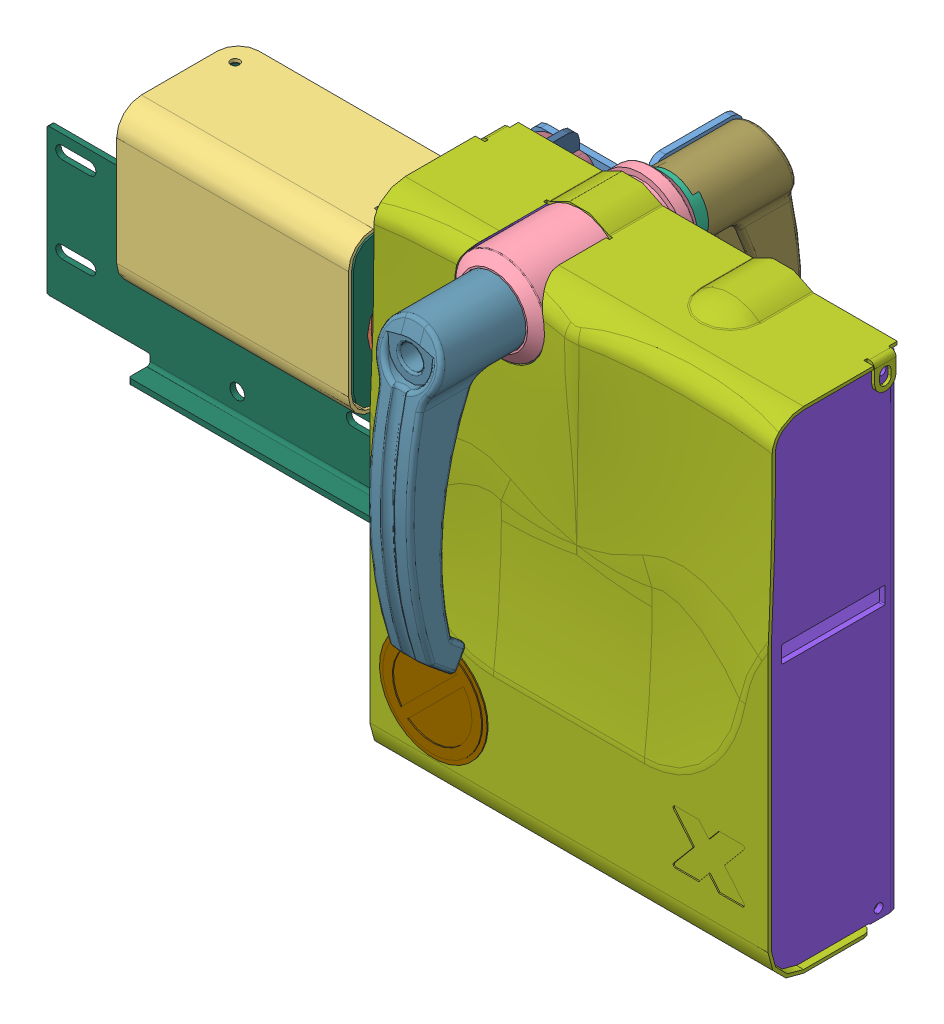
SolidWorks assembly L66-21-R, configuration Default. Lengths in mm.
Overall size (392.28 233 201.49).
16 component instances, 16 part files, 0 mates.
Components (placement in the parent):
- 00010380-1-1: 00010380-1 [Default] at (-32.9953 39.7 -87) x (0 0 -1) z (-1 0 0) size (45.2 80 53.67)
- 00005790_1-1-1: 00005790_1-1 [Default] at (-76.6694 0 30) x (0 0 1) z (1 0 0) size (34 55 11.73)
- 00008567-1-1: 00008567-1 [Default] at (-122.9194 40.05 6.45) x (0 -1 0) z (-1 0 0) size (73.4 56.45 107.7)
- 00005784_1-1-1: 00005784_1-1 [Default] x (-1 0 0) z (0 1 0) size (42 78.76 42)
- 00005791_1-1-1: 00005791_1-1 [Default] at (60.5 0 30) x (0 1 0) z (-1 0 0) size (25.01 25 182.37)
- 00005807-1-1: 00005807-1 [Default] at (0 50 -11.5) x (0 1 0) z (0 0 -1) size (30 30 12.5)
- 00008515-1-1: 00008515-1 [Default] at (34.75 -47.5 61.6) x (-1 0 0) z (0 1 0) size (187.44 67.56 233)
- 00008559_8-2450-90062-1-1-1: 00008559_8-2450-90062-1-1 [Default] at (30 -60 0) x (1 0 0) z (0 0 -1) size (179.5 225 62.42)
- 00009377_1-1-1: 00009377_1-1 [Default] at (-27.75 -119 61.6) x (0 -1 0) z (0 0 1) size (50 50 1)
- 00010380-1-1-1: 00010380-1-1 [Default] at (-63.9953 39.7 -42) x (0 0 -1) z (-1 0 0) size (45.2 80 53.67)
- 16-10010-1-1: 16-10010-1 [Default] at (-56 -30 -6.5) x (0 1 0) z (-1 0 0) size (60 31 54)
- Handtag_X-lock_Rött-1-1: Handtag_X-lock_Rött-1 [Default] at (30 -60 0) x (1 0 0) z (0 0 -1) size (31.2 144.06 57.99)
- 8-2450-04-1-1: 8-2450-04-1 [Default] at (-77.6694 30.7 -37.8) x (0 0 -1) z (-1 0 0) size (45 62 57)
- Handtag_X-lock_Svart-1-1: Handtag_X-lock_Svart-1 [Default] at (-30 -60 38.5) x (-1 0 0) z (0 0 1) size (31.2 144.06 57.99)
- 00010471_Höger-1: 00010471_Höger [Default] at (-404.4194 -35.45 3.2) x (-1 0 0) z (0 0 1) size (194.5 150.2 54.5)
- 00005776-1: 00005776 [Default] at (-51.5 -148.5 8) size (3.5 115 33)
